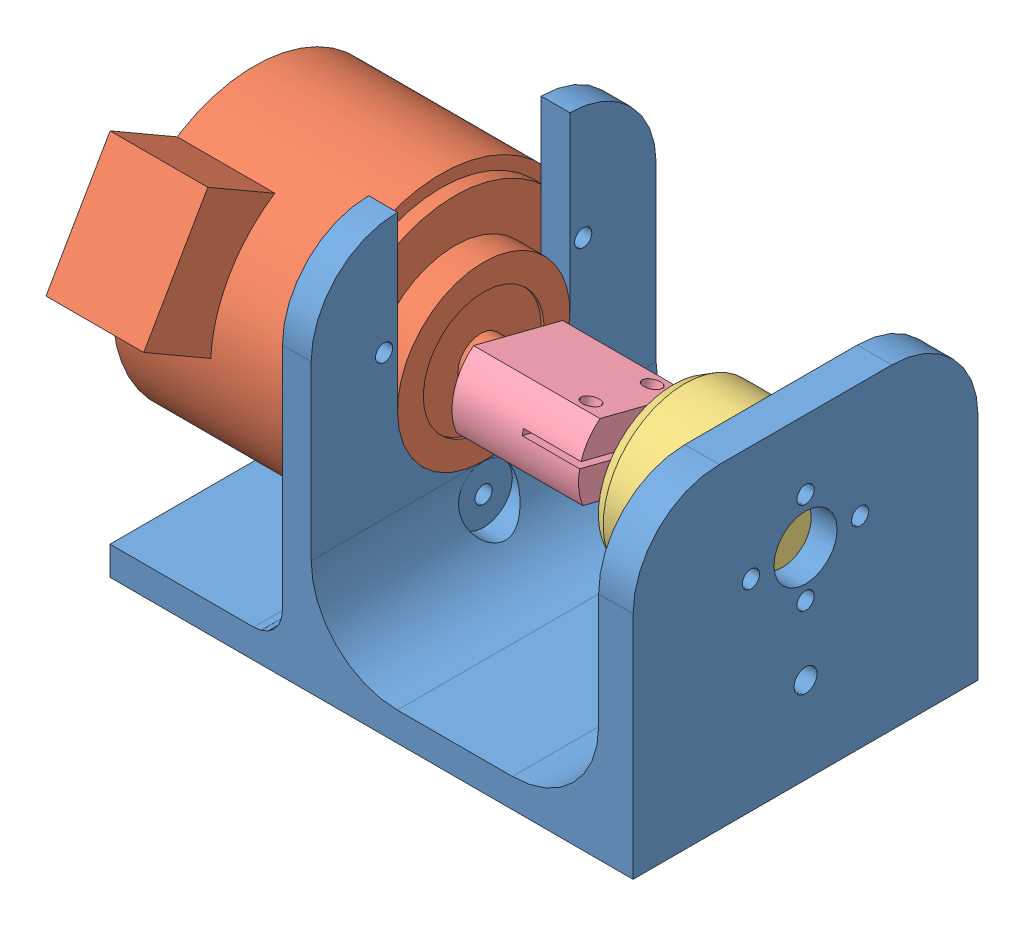
SolidWorks assembly AbsEnc_BLDC_testing, configuration Default. Lengths in mm.
Overall size (95.9 74 76.56).
4 component instances, 4 part files, 8 mates.
Components (placement in the parent):
- AbsEnc_mount-1: AbsEnc_mount [Default] at (-1.7883 43.8223 78.0183) size (91 65 60)
- Absolute Encoder-1: Absolute Encoder [Default] at (-13.601 60.1386 54.5641) x (0 -0.866025 0.5) z (0 0.5 0.866025) size (49.2 54.9 60)
- BLDC-1: BLDC [Default] at (83.2117 78.8223 108.0183) x (0 0 1) z (0 -1 0) size (28.4 32.5 28.4)
- shaft_adapter-1: shaft_adapter [Default] at (37.7117 78.8223 108.0183) x (1 0 0) z (0 0.248243 0.968698) size (22 12 20)
Mates (geometry in assembly coordinates):
- Concentric1: concentric aligned: cylinder of AbsEnc_mount-1 through (33.2117 78.8223 108.0183) axis (-1 0 0) radius 15; cylinder of Absolute Encoder-1 through (33.2117 78.8223 108.0183) axis (-1 0 0) radius 15
- Concentric2: concentric anti-aligned: cylinder of AbsEnc_mount-1 through (33.2117 88.8223 125.3388) axis (-1 0 0) radius 1.5; cylinder of Absolute Encoder-1 through (20.2117 88.8223 125.3388) axis (1 0 0) radius 1
- Coincident1: coincident anti-aligned: plane of AbsEnc_mount-1 through (28.2117 108.8223 138.0183) normal (-1 0 0); plane of Absolute Encoder-1 through (28.2117 78.8223 108.0183) normal (1 0 0)
- Concentric3: concentric aligned: cylinder of AbsEnc_mount-1 through (89.2117 78.8223 108.0183) axis (-1 0 0) radius 5.5; cylinder of BLDC-1 through (85.2117 78.8223 108.0183) axis (-1 0 0) radius 5
- Concentric4: concentric anti-aligned: cylinder of AbsEnc_mount-1 through (89.2117 78.8223 117.5183) axis (-1 0 0) radius 1.5; cylinder of BLDC-1 through (83.2117 78.8223 117.5183) axis (1 0 0) radius 1.5
- Coincident3: coincident anti-aligned: plane of AbsEnc_mount-1 through (83.2117 98.8223 138.0183) normal (-1 0 0); plane of BLDC-1 through (83.2117 78.8223 108.0183) normal (1 0 0)
- Concentric5: concentric aligned: cylinder of BLDC-1 through (52.7117 78.8223 108.0183) axis (1 0 0) radius 2.5; cylinder of shaft_adapter-1 through (49.7117 78.8223 108.0183) axis (1 0 0) radius 2.5
- Distance1: distance = 5 mm anti-aligned: plane of shaft_adapter-1 through (37.7117 78.8223 108.0183) normal (-1 0 0); plane of Absolute Encoder-1 through (32.7117 78.8223 108.0183) normal (1 0 0)
